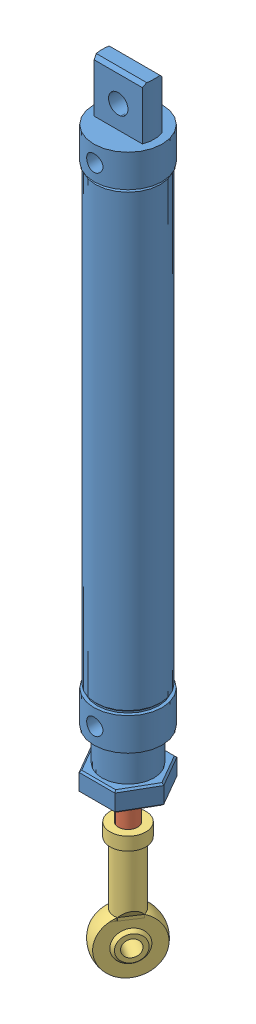
SolidWorks assembly MA16100SCA, configuration 默认. Lengths in mm.
Overall size (22 241.6 21.09).
3 component instances, 3 part files, 4 mates.
Components (placement in the parent):
- MA16100SCA-1: MA16100SCA [默认] at (-19.0112 -75.7853 192) size (22 192 21)
- MA16100SA杆-1: MA16100SA杆 [默认] at (-19.0112 8.2147 192) x (-0.101453 0 0.99484) z (0 -1 0) size (6 6 122)
- 224M5鱼眼轴承-dx-1: 224M5鱼眼轴承-dx [Default] at (-19.0112 -132.3853 192) x (-0.837169 0 -0.546944) z (0 1 0) size (11 18 40)
Mates (geometry in assembly coordinates):
- Concentric1: concentric: cylinder of assembly; cylinder of assembly; cylinder of MA16100SCA-1 through (-19.0112 8.2147 192) axis (0 -1 0) radius 3; cylinder of MA16100SA杆-1 through (-19.0112 -113.7853 192) axis (0 1 0) radius 3
- LimitDistance1: limit distance = 22 mm: plane of assembly; plane of assembly; plane of MA16100SA杆-1 through (-19.0112 -113.7853 192) normal (0 -1 0); plane of MA16100SCA-1 through (-19.0112 -91.7853 192) normal (0 -1 0)
- Concentric2: concentric: cylinder of assembly; cylinder of assembly; cylinder of MA16100SA杆-1 through (-19.0112 -113.7853 192) axis (0 1 0) radius 3; cylinder of 224M5鱼眼轴承-dx-1 through (-19.0112 -101.3853 192) axis (0 1 0) radius 2.1
- Coincident1: coincident: plane of assembly; circle of assembly; plane of MA16100SA杆-1 through (-19.0112 -113.7853 192) normal (0 -1 0); circle of 224M5鱼眼轴承-dx-1
